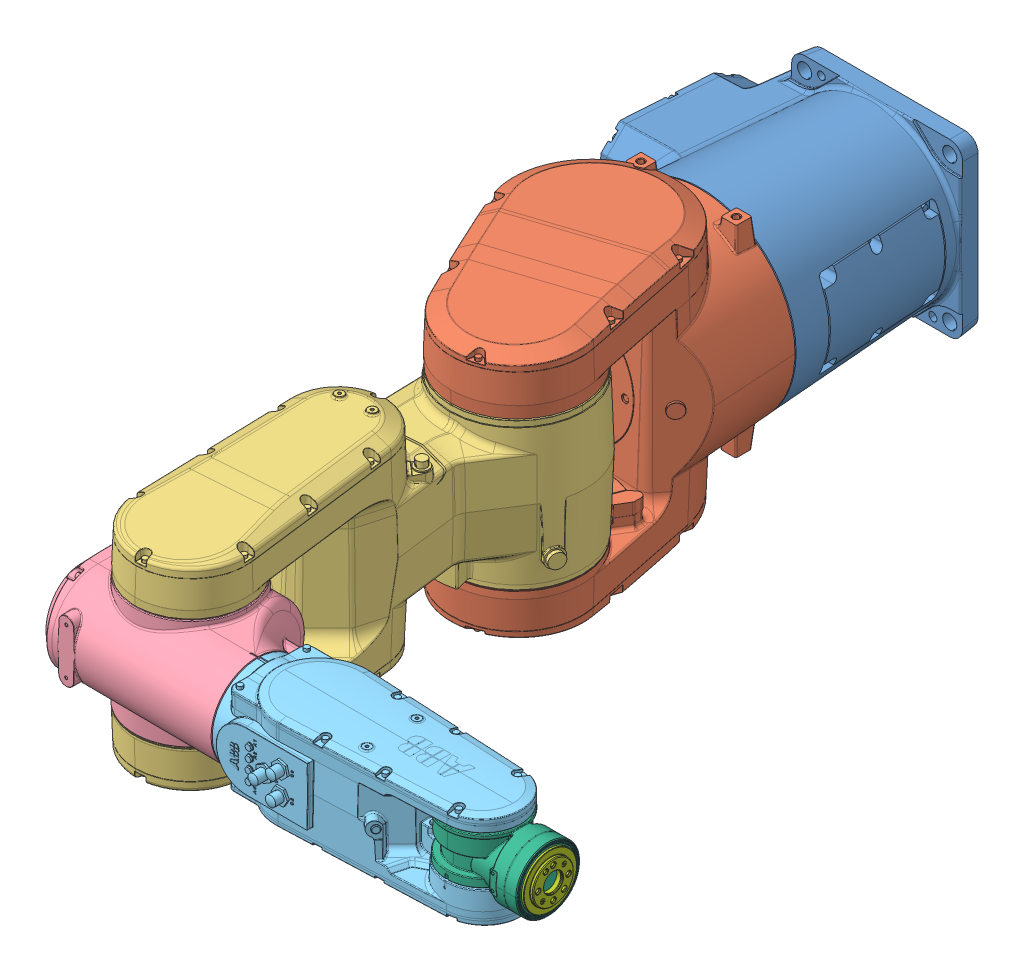
SolidWorks assembly Robot_Assemblato, configuration Default. Lengths in mm.
Overall size (760.79 340.77 1096.01).
7 component instances, 7 part files, 12 mates.
Components (placement in the parent):
- link0-rear cable_ORIENTATO-2: link0-rear cable_ORIENTATO [Default] at (-8.5802 -11.9735 192.6293) size (319.94 284.94 254.63)
- link1_900_DH-2: link1_900_DH [Default] at (29.0435 -14.0404 733.4993) x (0.999997 -0.002284 0) z (-0.002284 -0.999997 0) size (329.17 404.31 340.02)
- link2_900-2: link2_900 [Default] at (41.4576 -11.4428 1164.1053) x (-0.004118 0.000009 0.999992) z (-0.002284 -0.999997 0) size (601.23 189.02 278)
- link3-2: link3 [Default] at (39.724 -11.2697 1201.0702) x (-0.005056 0.000012 0.999987) z (0.999985 -0.002284 0.005056) size (197.44 160.88 236.33)
- link4_900-2: link4_900 [Default] at (463.5918 -12.2401 1204.2465) x (-0.005043 0.005411 0.999973) z (-0.002311 -0.999983 0.0054) size (148.27 345.08 126.82)
- link5-foundry.step-2: link5-foundry.step [Default] at (464.6454 -13.4154 1202.1635) x (0.005085 0.005388 0.999973) z (0.999984 -0.002339 -0.005072) size (123.45 84.83 136.6)
- link6-foundry-2: link6-foundry [Default] at (556.6807 -13.267 1203.2925) x (0.001914 -0.709674 0.704527) z (0.999984 -0.002339 -0.005072) size (70 70 11.7)
Mates (geometry in assembly coordinates):
- Concentrico3: concentric aligned: circle of link0-rear cable_ORIENTATO-2; circle of link1_900_DH-2
- Coincidente3: coincident anti-aligned: plane of link0-rear cable_ORIENTATO-2 through (-8.5802 -11.9735 446.6293) normal (0 0 1); plane of link1_900_DH-2 through (-87.4044 -118.8175 446.6293) normal (0 0 -1)
- Coincidente4: coincident anti-aligned: plane of link1_900_DH-2 through (41.1901 -112.5874 817.3573) normal (0.002284 0.999997 0); plane of link2_900-2 through (41.1901 -112.5874 736.6293) normal (-0.002284 -0.999997 0)
- Concentrico4: concentric aligned: circle of link1_900_DH-2; circle of link2_900-2
- Coincidente5: coincident anti-aligned: plane of link2_900-2 through (39.1701 -89.0827 1240.1251) normal (0.002284 0.999997 0); plane of link3-2 through (39.4934 -89.0835 1161.6257) normal (-0.002284 -0.999997 0)
- Concentrico7: concentric aligned: circle of link2_900-2; circle of link3-2
- Coincidente8: coincident anti-aligned: plane of link3-2 through (168.9651 -12.379 1202.28) normal (0.999985 -0.002284 0.005056); plane of link4_900-2 through (168.8148 -77.3779 1202.6309) normal (-0.999985 0.002284 -0.005056)
- Concentrico8: concentric aligned: circle of link3-2; circle of link4_900-2
- Coincidente10: coincident anti-aligned: plane of link4_900-2 through (464.4166 -32.0536 1203.8765) normal (0.002311 0.999983 -0.0054); plane of link5-foundry.step-2 through (464.4166 -32.0536 1203.8765) normal (-0.002311 -0.999983 0.0054)
- Concentrico9: concentric aligned: circle of link4_900-2; circle of link5-foundry.step-2
- Coincidente11: coincident anti-aligned: plane of link5-foundry.step-2 through (548.3818 -46.7498 1203.5288) normal (0.999984 -0.002339 -0.005072); plane of link6-foundry-2 through (548.4592 -13.2504 1203.3479) normal (-0.999984 0.002339 0.005072)
- Concentrico10: concentric anti-aligned: circle of link5-foundry.step-2; circle of link6-foundry-2
